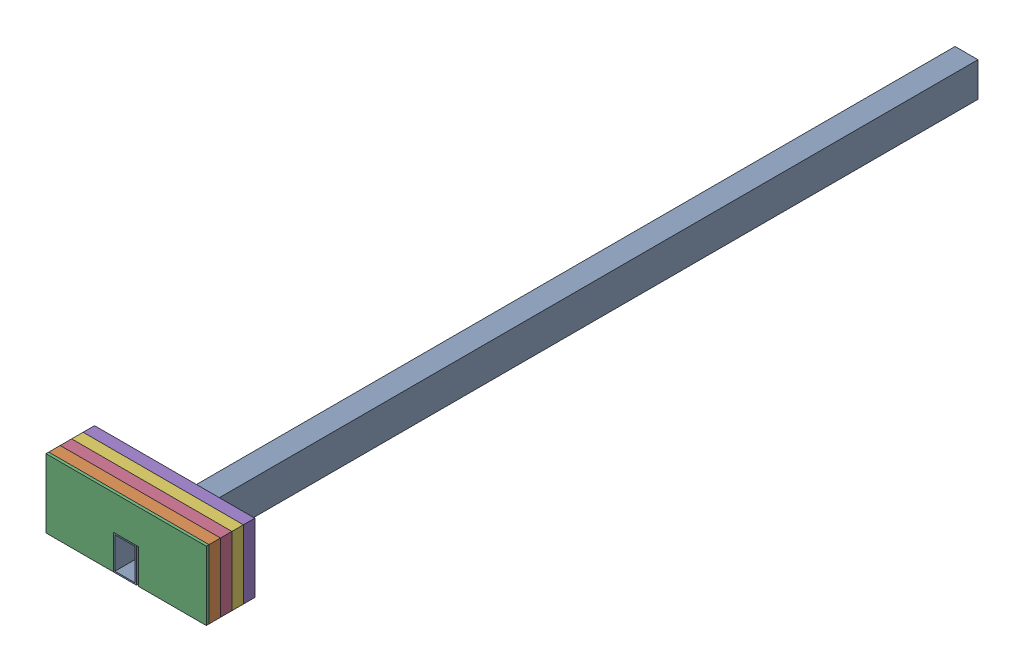
SolidWorks assembly Assembly_Crane, configuration Default. Lengths in mm.
Overall size (700 300 3675).
6 component instances, 3 part files, 7 mates.
Components (placement in the parent):
- Boom-1: Boom [Default] at origin size (100 150 3675)
- Weight-1: Weight [Default] at (355 -75 3613) size (700 300 50)
- Weight_Thin-1: Weight_Thin [Default] at (-345 -75 3663) size (700 300 12)
- Weight-2: Weight [Default] at (355 -75 3563) size (700 300 50)
- Weight-3: Weight [Default] at (355 -75 3463) size (700 300 50)
- Weight-4: Weight [Default] at (355 -75 3513) size (700 300 50)
Mates (geometry in assembly coordinates):
- Coincident1: coordinate: point of Boom-1
- Coincident2: coincident anti-aligned: plane of Weight-1 through (355 -75 3663) normal (0 0 1); plane of Weight_Thin-1 through (-345 -75 3663) normal (0 0 -1)
- Coincident3: coincident aligned: plane of Weight-1 through (355 225 3663) normal (1 0 0); plane of Weight_Thin-1 through (355 225 3675) normal (1 0 0)
- Coincident4: coincident aligned: plane of Weight-1 through (-345 225 3663) normal (0 1 0); plane of Weight_Thin-1 through (-345 225 3675) normal (0 1 0)
- Coincident5: coincident aligned: plane of Boom-1 through (0 0 3675) normal (0 0 1); plane of Weight_Thin-1 through (-345 -75 3675) normal (0 0 1)
- Coincident6: coincident anti-aligned: plane of Boom-1 through (-50 75 3675) normal (-1 0 0); plane of Weight_Thin-1 through (-50 75 3675) normal (1 0 0)
- Coincident7: coincident aligned: plane of Boom-1 through (-50 -75 3675) normal (0 -1 0); plane of Weight_Thin-1 through (-345 -75 3675) normal (0 -1 0)
